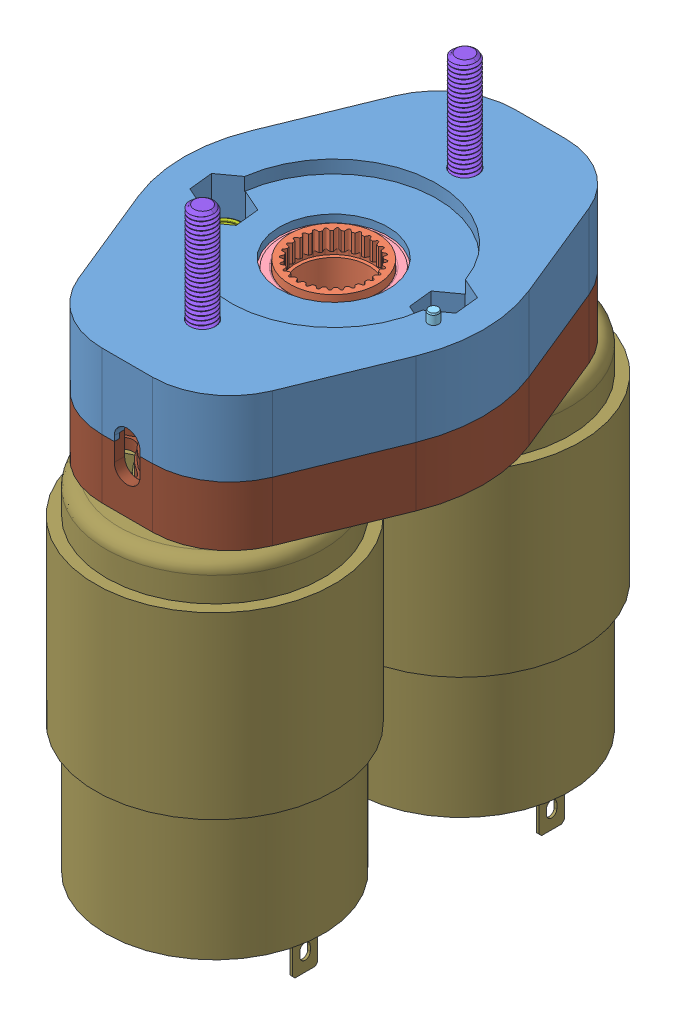
SolidWorks assembly 217-3141-RS775-STEP, configuration Default. Lengths in mm.
Overall size (58 120.42 93.95).
24 component instances, 13 part files, 0 mates.
Components (placement in the parent):
- 217-3141-001 Rev1-1: 217-3141-001 Rev1 [Default] x (0 0 1) z (-1 0 0) size (80 14.5 58)
- 217-3141-007 Rev1_30T 32DP-1: 217-3141-007 Rev1_30T 32DP [Default] at (0 -7.06 0) x (0 -1 0) z (-0.999183 0 0.040426) size (22.38 25.55 25.47)
- 217-3141-006 Rev1_30T 32DP-1: 217-3141-006 Rev1_30T 32DP [Default] at (0.8337 -9.0499 -23.8741) x (-0.095925 0 -0.995389) z (0 -1 0) size (25.47 25.55 10)
- 217-3141-006 Rev1_30T 32DP-2: 217-3141-006 Rev1_30T 32DP [Default] at (0.8337 -9.0499 23.8741) x (-0.001725 0 0.999999) z (0 -1 0) size (25.47 25.55 10)
- 217-2741-1: 217-2741 [Default] at (0 2.75 0) x (0 -1 0) z (-0.999445 0 -0.033298) size (5 26 26)
- 217-2741-2: 217-2741 [Default] at (0 -13.25 0) x (0 -1 0) z (-0.537831 0 0.843053) size (5 26 26)
- PINL-M020-006-S-1: PINL-M020-006-S [Default] at (22.7445 5.75 3.4184) x (0 1 0) z (-0.890225 0 0.455522) size (6 2 2)
- SSS1032-0188-ZB-1: SSS1032-0188-ZB [Default] at (0.4848 -10.9249 -27.4949) x (-0.758755 -0.647259 0.073121) z (0.095925 0 0.995389) size (4.91 4.91 5.06)
- SSS1032-0188-ZB-2: SSS1032-0188-ZB [Default] at (0.8274 -10.9249 27.5116) x (0.762269 -0.647259 0.001315) z (0.001725 0 -0.999999) size (4.91 4.91 5.06)
- NUT-832-NYLOCK-1: NUT-832-NYLOCK [Default] at (19.244 -4.75 -2.0226) x (0.913545 0 0.406737) z (-0.406737 0 0.913545) size (10.2 4.9 8.12)
- NUT-832-NYLOCK-2: NUT-832-NYLOCK [Default] at (-19.244 -4.75 2.0226) x (0.912648 0 0.408747) z (-0.408747 0 0.912648) size (10.2 4.9 8.12)
- 91251A346_91251A346-1: 91251A346_91251A346 [Default] at (0 25.975 25.4) x (1 0 0) z (0 1 0) size (7.92 7.92 27.28)
- 91251A346_91251A346-2: 91251A346_91251A346 [Default] at (0 25.975 -25.4) x (1 0 0) z (0 1 0) size (7.92 7.92 27.28)
- SSA_SSAM4-0010ZC-1: SSA_SSAM4-0010ZC [Default] at (12.5 -17.25 -23.8887) size (7 14 7)
- SSA_SSA0832-0750ZC-1: SSA_SSA0832-0750ZC [Default] at (19.244 -19.2499 -2.0226) x (-0.091926 0 -0.995766) z (-0.995766 0 0.091926) size (6.73 23.11 6.73)
- SSA_SSA0832-0750ZC-2: SSA_SSA0832-0750ZC [Default] at (-19.244 -19.2499 2.0226) x (-0.18632 0 -0.982489) z (-0.982489 0 0.18632) size (6.73 23.11 6.73)
- SSA_SSAM4-0010ZC-2: SSA_SSAM4-0010ZC [Default] at (-13.6663 -17.2499 23.8741) x (0.677756 0 0.735287) z (-0.735287 0 0.677756) size (7 14 7)
- SSA_SSAM4-0010ZC-3: SSA_SSAM4-0010ZC [Default] at (15.3337 -17.2499 23.8741) x (0.994338 0 -0.106265) z (0.106265 0 0.994338) size (7 14 7)
- SSA_SSAM4-0010ZC-4: SSA_SSAM4-0010ZC [Default] at (-13.6663 -17.2499 -23.8741) x (0.537906 0 -0.843005) z (0.843005 0 0.537906) size (7 14 7)
- 217-3141-004 Rev1-1: 217-3141-004 Rev1 [Default] at (0 -12.9999 0) x (0 0 1) z (0 1 0) size (80 58 12.5)
- BB RS775-18V-1: BB RS775-18V [Default] at (0.8337 -19.2499 23.8741) x (0 -1 0) z (0 0 1) size (88 46.2 46.2)
- BB RS775-18V-2: BB RS775-18V [Default] at (0.8337 -19.2499 -23.8741) x (0 -1 0) z (0 0 -1) size (88 46.2 46.2)
- 217-2625-013 Rev1-1: 217-2625-013 Rev1 [Default] at (0.8337 -10.1999 23.8741) x (1 0 0) z (0 1 0) size (8 7.93 7.5)
- 217-2625-013 Rev1-2: 217-2625-013 Rev1 [Default] at (0.8337 -10.1999 -23.8741) x (1 0 0) z (0 1 0) size (8 7.93 7.5)
